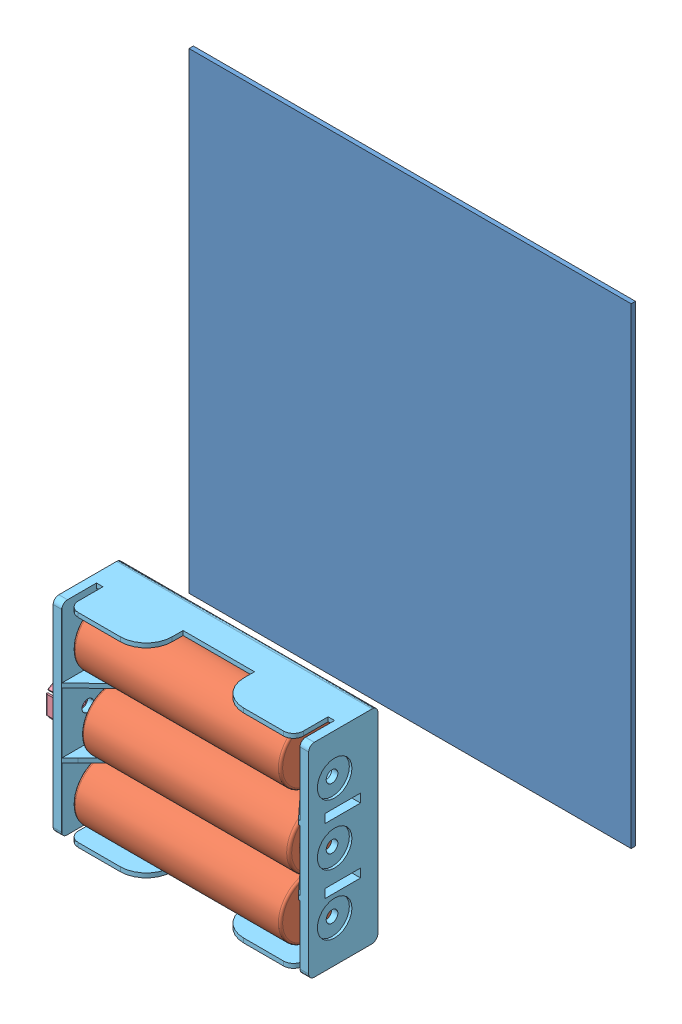
SolidWorks assembly FULL, configuration Default. Lengths in mm.
Overall size (123.67 108.97 143.43).
263 component instances, 61 part files, 2 mates.
Components (placement in the parent):
- PCB-1: PCB [Default] at origin size (102.11 108.97 21.15) (hidden)
  - Board-1: Board [Default] at origin size (102.11 108.97 0.41)
    - Open CASCADE STEP translator 6.8 2.1.1-1: Open CASCADE STEP translator 6.8 2.1.1 [Default] at (0 0 -0.4115) size (102.11 108.97 0.41)
  - arduino_nano-1: arduino_nano [Default] at (0 0 6.3234) size (45 18 18.6)
    - arduino_nano-1: arduino_nano [Default] at (189.4641 68.814 2.5274) x (-1 0 0) z (0 1 0) size (45 18.6 18)
      - nano-board-1: nano-board [Default] at origin size (43.2 4.61 18)
      - 2pin_header__02-1: 2pin_header__02 [Default] at (-1.143 1.6 -7.62) size (5 11.75 2.54)
      - 2pin_header__02-2: 2pin_header__02 [Default] at (-1.143 1.6 -5.08) size (5 11.75 2.54)
      - 2pin_header__02-3: 2pin_header__02 [Default] at (-1.143 1.6 -10.16) size (5 11.75 2.54)
      - 15pin_header__-1: 15pin_header__ [Default] x (0 0 1) z (1 0 0) size (2.54 11.75 38.1)
      - 15pin_header__-2: 15pin_header__ [Default] at (0 0 -15.24) x (0 0 1) z (1 0 0) size (2.54 11.75 38.1)
      - atmega328-1: atmega328 [Default] at (23.85 1.75 -7.62) x (-0.707107 0 0.707107) z (-0.707107 0 -0.707107) size (10 1.1 10)
      - ftdi_FT232rl-1: ftdi_FT232rl [Default] at (29.05 0 -7.67) x (0 0 -1) z (-1 0 0) size (9.25 1.9 10.2)
      - smt_resistor222-1: smt_resistor222 [Default] at (21.86 0 -5.8) x (0 0 -1) z (-1 0 0) size (1.7 0.6 3.8)
      - smt_resistor222-2: smt_resistor222 [Default] at (21.86 0 -9) x (0 0 -1) z (-1 0 0) size (1.7 0.6 3.8)
      - smt_resistor222-3: smt_resistor222 [Default] at (36.75 0 -7.6) x (0 0 -1) z (-1 0 0) size (1.7 0.6 3.8)
      - smt_resistor222-4: smt_resistor222 [Default] at (36.75 0 -12) x (0 0 -1) z (-1 0 0) size (1.7 0.6 3.8)
      - smt_resistor222-5: smt_resistor222 [Default] at (8.2 0 -2.6) x (0 0 -1) z (-1 0 0) size (1.7 0.6 3.8)
      - led-1: led [Default] at (10.4 1.6 -2.8) size (4 0.9 1.55)
      - led-2: led [Default] at (10.4 1.6 -5.55) size (4 0.9 1.55)
      - led-3: led [Default] at (10.4 1.6 -12.5) size (4 0.9 1.55)
      - led-4: led [Default] at (10.4 1.6 -9.05) size (4 0.9 1.55)
      - 16mhz_crystal_-_measured-1: 16mhz_crystal_-_measured [Default] at (18.5113 1.6 -3.5541) x (0.707107 0 0.707107) z (-0.707107 0 0.707107) size (3.4 0.8 2.01)
      - MINIUSB_-_MEASURED-1: MINIUSB_-_MEASURED [Default] at (38.98 1.65 -7.62) x (0 0 1) z (-1 0 0) size (10.9 4.96 10.42)
        - MINIUSBSHELL-1: MINIUSBSHELL [Default] at origin size (10.9 3.98 9.46)
        - MINIUSBCORE-1: MINIUSBCORE [Default] at (0 0 6.7) x (-1 0 0) z (0 0 -1) size (7.7 4.5 8.2)
        - MINI_USB_CONTACT-1: MINI_USB_CONTACT [Default] at (-1.6 0 5.7) x (-1 0 0) z (0 0 -1) size (0.53 2.55 9.41)
        - MINI_USB_CONTACT-2: MINI_USB_CONTACT [Default] at (-0.8 0 5.7) x (-1 0 0) z (0 0 -1) size (0.53 2.55 9.41)
        - MINI_USB_CONTACT-3: MINI_USB_CONTACT [Default] at (0 0 5.7) x (-1 0 0) z (0 0 -1) size (0.53 2.55 9.41)
        - MINI_USB_CONTACT-4: MINI_USB_CONTACT [Default] at (0.8 0 5.7) x (-1 0 0) z (0 0 -1) size (0.53 2.55 9.41)
        - MINI_USB_CONTACT-5: MINI_USB_CONTACT [Default] at (1.6 0 5.7) x (-1 0 0) z (0 0 -1) size (0.53 2.55 9.41)
      - cap106C-1: cap106C [Default] at (37.2 0 -3.3) x (0 0 1) z (1 0 0) size (1.7 1.81 4)
      - cap106C-2: cap106C [Default] at (7.9 0 -5.6) x (0 0 -1) z (-1 0 0) size (1.7 1.81 4)
      - reset_button-1: reset_button [Default] at (15.25 1.6 -8.05) x (0 0 -1) z (1 0 0) size (5.21 2.15 3)
        - reset_core-1: reset_core [Default] at origin size (5.21 2.15 2.8)
        - reset_shell-1: reset_shell [Default] at (0 1.65 0) x (0 0 1) z (-1 0 0) size (3 1.65 4)
      - nano_-_reg-1: nano_-_reg [Default] at (6.1 0 -10.16) x (0 0 -1) z (-1 0 0) size (6.5 1.69 8.3)
      - NANO_DIODE-1: NANO_DIODE [Default] at (11.43 0 -4.2) x (0 0 1) z (1 0 0) size (4.92 1.38 1.7)
      - 189_RESISTOR_PACK-1: 189_RESISTOR_PACK [Default] at (15.75 0 -10.85) x (0 0 1) z (1 0 0) size (3.2 0.51 3)
      - 102_RESISTOR_PACK-1: 102_RESISTOR_PACK [Default] at (15.75 0 -5.2) x (0 0 1) z (1 0 0) size (3.2 0.51 3)
  - M0-1: M0 [Default] at (0 0 4.4267) size (8.61 3.85 12.07)
    - SS12D00G4_1P2T_Straight-1: SS12D00G4_1P2T_Straight [Default] at (146.8249 131.405 2.54) x (1 0 0) z (0 0 1) size (8.61 3.85 12.07)
  - BMP-1: BMP [Default] at (0 0 2.9006) size (13.55 10.7 12.7)
    - GY-BME280-1: GY-BME280 [Default] at (155.5751 97.6629 0) x (0 1 0) z (0 0 1) size (10.7 13.55 3.64)
    - 1185083472-1: 1185083472 [Default] at (154.178 97.536 0) size (2.54 10.16 2.8)
      - Extruded-1: Extruded [Default] at origin size (2.54 10.16 2.8)
    - 1185083552-1: 1185083552 [Default] at (154.1779 93.7261 -3.2) x (0 1 0) z (0 0 1) size (1.06 1.06 12.7)
      - Cylinder-1: Cylinder [Default] at origin size (1.06 1.06 12.7)
    - 1185083552-2: 1185083552 [Default] at (154.1779 96.2661 -3.2) x (0 1 0) z (0 0 1) size (1.06 1.06 12.7)
      - Cylinder-1: Cylinder [Default] at origin size (1.06 1.06 12.7)
    - 1185083552-3: 1185083552 [Default] at (154.1779 98.8061 -3.2) x (0 1 0) z (0 0 1) size (1.06 1.06 12.7)
      - Cylinder-1: Cylinder [Default] at origin size (1.06 1.06 12.7)
    - 1185083552-4: 1185083552 [Default] at (154.1779 101.3461 -3.2) x (0 1 0) z (0 0 1) size (1.06 1.06 12.7)
      - Cylinder-1: Cylinder [Default] at origin size (1.06 1.06 12.7)
  - LVL_CONV-1: LVL_CONV [Default] at origin size (26 16 2.26)
    - TXS0108E-1: TXS0108E [Default] at (183.8961 73.6876 0) x (-1 0 0) z (0 1 0) size (26 2.26 16)
  - GPS-1: GPS [Default] at (0 0 9.8364) size (25.78 64.21 19.66)
    - GNSS_7_Click_v100_noAntenna-1: GNSS_7_Click_v100_noAntenna [Default] at (180.3023 96.7993 0.254) x (1 0 0) z (0 0 1) size (25.78 64.21 19.66)
      - GNSS_7_Click_v100.step-1: GNSS_7_Click_v100.step [Default] at origin size (25.78 64.21 19.66)
        - JP4.step-1: JP4.step [Default] at origin size (0.5 1 0.35)
          - User_Library-R_0402.step-1: User_Library-R_0402.step [Default] at (12.3191 18.1685 0) x (0 -1 0) z (0 0 1) size (1 0.5 0.35)
        - JP3.step-1: JP3.step [Default] at origin size (0.5 1 0.35)
          - User_Library-R_0402.step-1: User_Library-R_0402.step [Default] at (10.9221 18.161 0) x (0 -1 0) z (0 0 1) size (1 0.5 0.35)
        - JP2.step-1: JP2.step [Default] at origin size (0.5 1 0.35)
          - User_Library-R_0402.step-1: User_Library-R_0402.step [Default] at (9.5251 18.1685 0) x (0 -1 0) z (0 0 1) size (1 0.5 0.35)
        - JP1.step-1: JP1.step [Default] at origin size (0.5 1 0.35)
          - User_Library-R_0402.step-1: User_Library-R_0402.step [Default] at (8.1281 18.1685 0) x (0 -1 0) z (0 0 1) size (1 0.5 0.35)
        - MBD1.step-1: MBD1.step [Default] at origin size (25.78 20.32 12.19)
          - Header_1x8.step-1: Header_1x8.step [Default] at (-74.8548 -67.056 0) size (2.92 20.32 12.19)
            - PCB.step-1: PCB.step [Default] at origin size (2.92 20.32 12.19)
              - Free-Models.step-1: Free-Models.step [Default] at origin size (2.92 20.32 12.19)
                - 1240637040.step-1: 1240637040.step [Default] at (97.7778 84.836 -1.6002) x (0 -1 0) z (1 0 0) size (12.7 12.19 2.92)
                  - User_Library-PinHeaderX5-1_PinHeaderX5_Body_1.step-1: User_Library-PinHeaderX5-1_PinHeaderX5_Body_1.step [Default] at origin size (12.7 2.54 2.92)
                  - User_Library-PinHeaderX5-1_PinHeaderX5_Pins_1.step-1: User_Library-PinHeaderX5-1_PinHeaderX5_Pins_1.step [Default] at origin size (10.8 12.19 0.64)
                - 1240637040.step-2: 1240637040.step [Default] at (97.7778 77.216 -1.6002) x (0 -1 0) z (1 0 0) size (12.7 12.19 2.92)
                  - User_Library-PinHeaderX5-1_PinHeaderX5_Body_1.step-1: User_Library-PinHeaderX5-1_PinHeaderX5_Body_1.step [Default] at origin size (12.7 2.54 2.92)
                  - User_Library-PinHeaderX5-1_PinHeaderX5_Pins_1.step-1: User_Library-PinHeaderX5-1_PinHeaderX5_Pins_1.step [Default] at origin size (10.8 12.19 0.64)
          - Header_1x8.step-2: Header_1x8.step [Default] at (-97.7148 -67.056 0) size (2.92 20.32 12.19)
            - PCB.step-1: PCB.step [Default] at origin size (2.92 20.32 12.19)
              - Free-Models.step-1: Free-Models.step [Default] at origin size (2.92 20.32 12.19)
                - 1240637040.step-1: 1240637040.step [Default] at (97.7778 84.836 -1.6002) x (0 -1 0) z (1 0 0) size (12.7 12.19 2.92)
                  - User_Library-PinHeaderX5-1_PinHeaderX5_Body_1.step-1: User_Library-PinHeaderX5-1_PinHeaderX5_Body_1.step [Default] at origin size (12.7 2.54 2.92)
                  - User_Library-PinHeaderX5-1_PinHeaderX5_Pins_1.step-1: User_Library-PinHeaderX5-1_PinHeaderX5_Pins_1.step [Default] at origin size (10.8 12.19 0.64)
                - 1240637040.step-2: 1240637040.step [Default] at (97.7778 77.216 -1.6002) x (0 -1 0) z (1 0 0) size (12.7 12.19 2.92)
                  - User_Library-PinHeaderX5-1_PinHeaderX5_Body_1.step-1: User_Library-PinHeaderX5-1_PinHeaderX5_Body_1.step [Default] at origin size (12.7 2.54 2.92)
                  - User_Library-PinHeaderX5-1_PinHeaderX5_Pins_1.step-1: User_Library-PinHeaderX5-1_PinHeaderX5_Pins_1.step [Default] at origin size (10.8 12.19 0.64)
        - M1.step-1: M1.step [Default] at origin size (16 12.2 2.33)
          - NEO.step-1: NEO.step [Default] at (27.1803 74.1975 0.44) x (0 1 0) z (0 0 1) size (12.2 16 2.33)
            - NEO_PCB.step-1: NEO_PCB.step [Default] at (-47.5276 18.1124 -0.4125) size (12.2 16 0.9)
            - Shield_NEO.step-1: Shield_NEO.step [Default] at (-52.9276 25.2124 1.8175) x (0 -1 0) z (-1 0 0) size (15 1.4 11.6)
            - u-blox_NEO_label.step-1: u-blox_NEO_label.step [Default] at (-47.5276 18.1124 1.8175) x (0 1 0) z (1 0 0) size (13 0.07 10)
        - L1.step-1: L1.step [Default] at origin size (1 0.6 0.5)
          - User_Library-Chip_InductorINDC1005X60N.step-1: User_Library-Chip_InductorINDC1005X60N.step [Default] at (4.191 38.435 0.2433) x (1 0 0) z (0 0 1) size (1 0.6 0.5)
        - R9.step-1: R9.step [Default] at origin size (3.2 1.6 0.6)
          - User_Library-R_1206.step-1: User_Library-R_1206.step [Default] at (7.197 41.0209 0) x (-1 0 0) z (0 0 1) size (3.2 1.6 0.6)
        - C6.step-1: C6.step [Default] at origin size (2 1.25 0.6)
          - User_Library-SMD_CAPACITOR0805.step-1: User_Library-SMD_CAPACITOR0805.step [Default] at (7.7471 38.7351 0.3) x (1 0 0) z (0 -1 0) size (2 0.6 1.25)
        - R8.step-1: R8.step [Default] at origin size (1.6 0.9 0.5)
          - User_Library-R_0603.step-1: User_Library-R_0603.step [Default] at (19.8119 26.289 0) x (-1 0 0) z (0 0 1) size (1.6 0.9 0.5)
        - C3.step-1: C3.step [Default] at origin size (0.8 1.6 0.8)
          - User_Library-SMD_CAPACITOR0603.step-1: User_Library-SMD_CAPACITOR0603.step [Default] at (15.8749 17.7801 0.39) x (0 1 0) z (0 0 1) size (1.6 0.8 0.8)
        - C2.step-1: C2.step [Default] at origin size (0.8 1.6 0.8)
          - User_Library-SMD_CAPACITOR0603.step-1: User_Library-SMD_CAPACITOR0603.step [Default] at (13.9699 17.7801 0.39) x (0 1 0) z (0 0 1) size (1.6 0.8 0.8)
        - U2.step-1: U2.step [Default] at origin size (2.9 2.8 1.45)
          - User_Library-SOT23-5-2.step-1: User_Library-SOT23-5-2.step [Default] at (19.812 33.2739 0) x (-1 0 0) z (0 0 1) size (2.9 2.8 1.45)
        - U1.step-1: U1.step [Default] at origin size (2.9 2.82 1)
          - TSOT-23-6(S6).step-1: TSOT-23-6(S6).step [Default] at (19.1769 39.878 0) x (0 1 0) z (1 0 0) size (2.82 1 2.9)
        - R7.step-1: R7.step [Default] at origin size (0.9 1.6 0.5)
          - User_Library-R_0603.step-1: User_Library-R_0603.step [Default] at (12.446 35.8141 0) x (0 1 0) z (0 0 1) size (1.6 0.9 0.5)
        - R6.step-1: R6.step [Default] at origin size (0.9 1.6 0.5)
          - User_Library-R_0603.step-1: User_Library-R_0603.step [Default] at (10.922 35.8141 0) x (0 1 0) z (0 0 1) size (1.6 0.9 0.5)
        - R5.step-1: R5.step [Default] at origin size (0.9 1.6 0.5)
          - User_Library-R_0603.step-1: User_Library-R_0603.step [Default] at (9.398 35.8139 0) x (0 -1 0) z (0 0 1) size (1.6 0.9 0.5)
        - R4.step-1: R4.step [Default] at origin size (0.9 1.6 0.5)
          - User_Library-R_0603.step-1: User_Library-R_0603.step [Default] at (22.86 28.9559 0) x (0 -1 0) z (0 0 1) size (1.6 0.9 0.5)
        - R3.step-1: R3.step [Default] at origin size (1.6 0.9 0.5)
          - User_Library-R_0603.step-1: User_Library-R_0603.step [Default] at (19.8119 28.194 0) x (-1 0 0) z (0 0 1) size (1.6 0.9 0.5)
        - R2.step-1: R2.step [Default] at origin size (1.6 0.9 0.5)
          - User_Library-R_0603.step-1: User_Library-R_0603.step [Default] at (19.8119 30.099 0) x (-1 0 0) z (0 0 1) size (1.6 0.9 0.5)
        - R1.step-1: R1.step [Default] at origin size (2 1.25 0.5)
          - User_Library-R_0805.step-1: User_Library-R_0805.step [Default] at (12.1919 1.1429 0) x (-1 0 0) z (0 0 1) size (2 1.25 0.5)
        - Q1.step-1: Q1.step [Default] at origin size (2.25 2.2 1.1)
          - SOT323_(SC70-3)-1.step-1: SOT323_(SC70-3)-1.step [Default] at (15.3671 35.8141 0) x (0 -1 0) z (-1 0 0) size (2.2 1.1 2.25)
            - User_Library-SOT323_(SC70-3)-1_K_X_F6rper_1.step-1: User_Library-SOT323_(SC70-3)-1_K_X_F6rper_1.step [Default] x (0 0 -1) z (0 1 0) size (1.35 2.2 1)
            - User_Library-SOT323_(SC70-3)-1_Beschriftung_1.step-1: User_Library-SOT323_(SC70-3)-1_Beschriftung_1.step [Default] x (0 0 -1) z (0 1 0) size (0.8 1.45 0.06)
            - User_Library-SOT323_(SC70-3)-1_Pins_1.step-1: User_Library-SOT323_(SC70-3)-1_Pins_1.step [Default] at (0.65 0 0) x (0 0 1) z (0 1 0) size (0.6 0.4 0.9)
            - User_Library-SOT323_(SC70-3)-1_Pins_1.step-2: User_Library-SOT323_(SC70-3)-1_Pins_1.step [Default] at (-0.65 0 0) x (0 0 1) z (0 1 0) size (0.6 0.4 0.9)
            - User_Library-SOT323_(SC70-3)-1_Pins_1.step-3: User_Library-SOT323_(SC70-3)-1_Pins_1.step [Default] x (0 0 -1) z (0 1 0) size (0.6 0.4 0.9)
        - LD2.step-1: LD2.step [Default] at origin size (2.1 1.35 0.91)
          - CHIPLED-0805-RED.step-1: CHIPLED-0805-RED.step [Default] at (20.7009 21.3361 0) x (0 1 0) z (0 0 1) size (1.35 2.1 0.91)
        - LD1.step-1: LD1.step [Default] at origin size (2.02 1.25 1.1)
          - led_0805_green.step-1: led_0805_green.step [Default] at (16.5099 1.143 0) x (-1 0 0) z (0 0 1) size (2.02 1.25 1.1)
        - CN2.step-1: CN2.step [Default] at origin size (6.35 14.81 13.49)
          - User_Library-sma_ra_pcb_mount_molex.step-1: User_Library-sma_ra_pcb_mount_molex.step [Default] at (3.302 48.7682 0) x (0 1 0) z (0 0 1) size (14.81 6.35 13.49)
        - C5.step-1: C5.step [Default] at origin size (0.8 1.6 0.8)
          - User_Library-SMD_CAPACITOR0603.step-1: User_Library-SMD_CAPACITOR0603.step [Default] at (22.8791 32.8929 0.39) x (0 -1 0) z (0 0 1) size (1.6 0.8 0.8)
        - C4.step-1: C4.step [Default] at origin size (1.6 0.8 0.8)
          - User_Library-SMD_CAPACITOR0603.step-1: User_Library-SMD_CAPACITOR0603.step [Default] at (19.8121 36.4491 0.39) size (1.6 0.8 0.8)
        - C1.step-1: C1.step [Default] at origin size (3.7 2.93 2.03)
          - User_Library-AVX_BCASE.step-1: User_Library-AVX_BCASE.step [Default] at (7.0351 1.1431 0) x (1 0 0) z (0 0 1) size (3.7 2.93 2.03)
        - BAT1.step-1: BAT1.step [Default] at origin size (8 10.71 3.05)
          - keystone-PN2998TR.step-1: keystone-PN2998TR.step [Default] at (5.2705 9.272 2.9) x (0 -1 0) z (-1 0 0) size (10.71 3.05 8)
        - Board.step-1: Board.step [Default] at origin size (25.4 57.15 1.59)
  - GAL-1: GAL [Default] at (0 0 11.1875) size (25.78 64.21 19.66)
    - GNSS_7_Click_v100_noAntenna-1: GNSS_7_Click_v100_noAntenna [Default] at (211.1003 96.5199 0) x (1 0 0) z (0 0 1) size (25.78 64.21 19.66)
      - GNSS_7_Click_v100.step-1: GNSS_7_Click_v100.step [Default] at origin size (25.78 64.21 19.66)
        - JP4.step-1: JP4.step [Default] at origin size (0.5 1 0.35)
          - User_Library-R_0402.step-1: User_Library-R_0402.step [Default] at (12.3191 18.1685 0) x (0 -1 0) z (0 0 1) size (1 0.5 0.35)
        - JP3.step-1: JP3.step [Default] at origin size (0.5 1 0.35)
          - User_Library-R_0402.step-1: User_Library-R_0402.step [Default] at (10.9221 18.161 0) x (0 -1 0) z (0 0 1) size (1 0.5 0.35)
        - JP2.step-1: JP2.step [Default] at origin size (0.5 1 0.35)
          - User_Library-R_0402.step-1: User_Library-R_0402.step [Default] at (9.5251 18.1685 0) x (0 -1 0) z (0 0 1) size (1 0.5 0.35)
        - JP1.step-1: JP1.step [Default] at origin size (0.5 1 0.35)
          - User_Library-R_0402.step-1: User_Library-R_0402.step [Default] at (8.1281 18.1685 0) x (0 -1 0) z (0 0 1) size (1 0.5 0.35)
        - MBD1.step-1: MBD1.step [Default] at origin size (25.78 20.32 12.19)
          - Header_1x8.step-1: Header_1x8.step [Default] at (-74.8548 -67.056 0) size (2.92 20.32 12.19)
            - PCB.step-1: PCB.step [Default] at origin size (2.92 20.32 12.19)
              - Free-Models.step-1: Free-Models.step [Default] at origin size (2.92 20.32 12.19)
                - 1240637040.step-1: 1240637040.step [Default] at (97.7778 84.836 -1.6002) x (0 -1 0) z (1 0 0) size (12.7 12.19 2.92)
                  - User_Library-PinHeaderX5-1_PinHeaderX5_Body_1.step-1: User_Library-PinHeaderX5-1_PinHeaderX5_Body_1.step [Default] at origin size (12.7 2.54 2.92)
                  - User_Library-PinHeaderX5-1_PinHeaderX5_Pins_1.step-1: User_Library-PinHeaderX5-1_PinHeaderX5_Pins_1.step [Default] at origin size (10.8 12.19 0.64)
                - 1240637040.step-2: 1240637040.step [Default] at (97.7778 77.216 -1.6002) x (0 -1 0) z (1 0 0) size (12.7 12.19 2.92)
                  - User_Library-PinHeaderX5-1_PinHeaderX5_Body_1.step-1: User_Library-PinHeaderX5-1_PinHeaderX5_Body_1.step [Default] at origin size (12.7 2.54 2.92)
                  - User_Library-PinHeaderX5-1_PinHeaderX5_Pins_1.step-1: User_Library-PinHeaderX5-1_PinHeaderX5_Pins_1.step [Default] at origin size (10.8 12.19 0.64)
          - Header_1x8.step-2: Header_1x8.step [Default] at (-97.7148 -67.056 0) size (2.92 20.32 12.19)
            - PCB.step-1: PCB.step [Default] at origin size (2.92 20.32 12.19)
              - Free-Models.step-1: Free-Models.step [Default] at origin size (2.92 20.32 12.19)
                - 1240637040.step-1: 1240637040.step [Default] at (97.7778 84.836 -1.6002) x (0 -1 0) z (1 0 0) size (12.7 12.19 2.92)
                  - User_Library-PinHeaderX5-1_PinHeaderX5_Body_1.step-1: User_Library-PinHeaderX5-1_PinHeaderX5_Body_1.step [Default] at origin size (12.7 2.54 2.92)
                  - User_Library-PinHeaderX5-1_PinHeaderX5_Pins_1.step-1: User_Library-PinHeaderX5-1_PinHeaderX5_Pins_1.step [Default] at origin size (10.8 12.19 0.64)
                - 1240637040.step-2: 1240637040.step [Default] at (97.7778 77.216 -1.6002) x (0 -1 0) z (1 0 0) size (12.7 12.19 2.92)
                  - User_Library-PinHeaderX5-1_PinHeaderX5_Body_1.step-1: User_Library-PinHeaderX5-1_PinHeaderX5_Body_1.step [Default] at origin size (12.7 2.54 2.92)
                  - User_Library-PinHeaderX5-1_PinHeaderX5_Pins_1.step-1: User_Library-PinHeaderX5-1_PinHeaderX5_Pins_1.step [Default] at origin size (10.8 12.19 0.64)
        - M1.step-1: M1.step [Default] at origin size (16 12.2 2.33)
          - NEO.step-1: NEO.step [Default] at (27.1803 74.1975 0.44) x (0 1 0) z (0 0 1) size (12.2 16 2.33)
            - NEO_PCB.step-1: NEO_PCB.step [Default] at (-47.5276 18.1124 -0.4125) size (12.2 16 0.9)
            - Shield_NEO.step-1: Shield_NEO.step [Default] at (-52.9276 25.2124 1.8175) x (0 -1 0) z (-1 0 0) size (15 1.4 11.6)
            - u-blox_NEO_label.step-1: u-blox_NEO_label.step [Default] at (-47.5276 18.1124 1.8175) x (0 1 0) z (1 0 0) size (13 0.07 10)
        - L1.step-1: L1.step [Default] at origin size (1 0.6 0.5)
          - User_Library-Chip_InductorINDC1005X60N.step-1: User_Library-Chip_InductorINDC1005X60N.step [Default] at (4.191 38.435 0.2433) x (1 0 0) z (0 0 1) size (1 0.6 0.5)
        - R9.step-1: R9.step [Default] at origin size (3.2 1.6 0.6)
          - User_Library-R_1206.step-1: User_Library-R_1206.step [Default] at (7.197 41.0209 0) x (-1 0 0) z (0 0 1) size (3.2 1.6 0.6)
        - C6.step-1: C6.step [Default] at origin size (2 1.25 0.6)
          - User_Library-SMD_CAPACITOR0805.step-1: User_Library-SMD_CAPACITOR0805.step [Default] at (7.7471 38.7351 0.3) x (1 0 0) z (0 -1 0) size (2 0.6 1.25)
        - R8.step-1: R8.step [Default] at origin size (1.6 0.9 0.5)
          - User_Library-R_0603.step-1: User_Library-R_0603.step [Default] at (19.8119 26.289 0) x (-1 0 0) z (0 0 1) size (1.6 0.9 0.5)
        - C3.step-1: C3.step [Default] at origin size (0.8 1.6 0.8)
          - User_Library-SMD_CAPACITOR0603.step-1: User_Library-SMD_CAPACITOR0603.step [Default] at (15.8749 17.7801 0.39) x (0 1 0) z (0 0 1) size (1.6 0.8 0.8)
        - C2.step-1: C2.step [Default] at origin size (0.8 1.6 0.8)
          - User_Library-SMD_CAPACITOR0603.step-1: User_Library-SMD_CAPACITOR0603.step [Default] at (13.9699 17.7801 0.39) x (0 1 0) z (0 0 1) size (1.6 0.8 0.8)
        - U2.step-1: U2.step [Default] at origin size (2.9 2.8 1.45)
          - User_Library-SOT23-5-2.step-1: User_Library-SOT23-5-2.step [Default] at (19.812 33.2739 0) x (-1 0 0) z (0 0 1) size (2.9 2.8 1.45)
        - U1.step-1: U1.step [Default] at origin size (2.9 2.82 1)
          - TSOT-23-6(S6).step-1: TSOT-23-6(S6).step [Default] at (19.1769 39.878 0) x (0 1 0) z (1 0 0) size (2.82 1 2.9)
        - R7.step-1: R7.step [Default] at origin size (0.9 1.6 0.5)
          - User_Library-R_0603.step-1: User_Library-R_0603.step [Default] at (12.446 35.8141 0) x (0 1 0) z (0 0 1) size (1.6 0.9 0.5)
        - R6.step-1: R6.step [Default] at origin size (0.9 1.6 0.5)
          - User_Library-R_0603.step-1: User_Library-R_0603.step [Default] at (10.922 35.8141 0) x (0 1 0) z (0 0 1) size (1.6 0.9 0.5)
        - R5.step-1: R5.step [Default] at origin size (0.9 1.6 0.5)
          - User_Library-R_0603.step-1: User_Library-R_0603.step [Default] at (9.398 35.8139 0) x (0 -1 0) z (0 0 1) size (1.6 0.9 0.5)
        - R4.step-1: R4.step [Default] at origin size (0.9 1.6 0.5)
          - User_Library-R_0603.step-1: User_Library-R_0603.step [Default] at (22.86 28.9559 0) x (0 -1 0) z (0 0 1) size (1.6 0.9 0.5)
        - R3.step-1: R3.step [Default] at origin size (1.6 0.9 0.5)
          - User_Library-R_0603.step-1: User_Library-R_0603.step [Default] at (19.8119 28.194 0) x (-1 0 0) z (0 0 1) size (1.6 0.9 0.5)
        - R2.step-1: R2.step [Default] at origin size (1.6 0.9 0.5)
          - User_Library-R_0603.step-1: User_Library-R_0603.step [Default] at (19.8119 30.099 0) x (-1 0 0) z (0 0 1) size (1.6 0.9 0.5)
        - R1.step-1: R1.step [Default] at origin size (2 1.25 0.5)
          - User_Library-R_0805.step-1: User_Library-R_0805.step [Default] at (12.1919 1.1429 0) x (-1 0 0) z (0 0 1) size (2 1.25 0.5)
        - Q1.step-1: Q1.step [Default] at origin size (2.25 2.2 1.1)
          - SOT323_(SC70-3)-1.step-1: SOT323_(SC70-3)-1.step [Default] at (15.3671 35.8141 0) x (0 -1 0) z (-1 0 0) size (2.2 1.1 2.25)
            - User_Library-SOT323_(SC70-3)-1_K_X_F6rper_1.step-1: User_Library-SOT323_(SC70-3)-1_K_X_F6rper_1.step [Default] x (0 0 -1) z (0 1 0) size (1.35 2.2 1)
            - User_Library-SOT323_(SC70-3)-1_Beschriftung_1.step-1: User_Library-SOT323_(SC70-3)-1_Beschriftung_1.step [Default] x (0 0 -1) z (0 1 0) size (0.8 1.45 0.06)
            - User_Library-SOT323_(SC70-3)-1_Pins_1.step-1: User_Library-SOT323_(SC70-3)-1_Pins_1.step [Default] at (0.65 0 0) x (0 0 1) z (0 1 0) size (0.6 0.4 0.9)
            - User_Library-SOT323_(SC70-3)-1_Pins_1.step-2: User_Library-SOT323_(SC70-3)-1_Pins_1.step [Default] at (-0.65 0 0) x (0 0 1) z (0 1 0) size (0.6 0.4 0.9)
            - User_Library-SOT323_(SC70-3)-1_Pins_1.step-3: User_Library-SOT323_(SC70-3)-1_Pins_1.step [Default] x (0 0 -1) z (0 1 0) size (0.6 0.4 0.9)
        - LD2.step-1: LD2.step [Default] at origin size (2.1 1.35 0.91)
          - CHIPLED-0805-RED.step-1: CHIPLED-0805-RED.step [Default] at (20.7009 21.3361 0) x (0 1 0) z (0 0 1) size (1.35 2.1 0.91)
        - LD1.step-1: LD1.step [Default] at origin size (2.02 1.25 1.1)
          - led_0805_green.step-1: led_0805_green.step [Default] at (16.5099 1.143 0) x (-1 0 0) z (0 0 1) size (2.02 1.25 1.1)
        - CN2.step-1: CN2.step [Default] at origin size (6.35 14.81 13.49)
          - User_Library-sma_ra_pcb_mount_molex.step-1: User_Library-sma_ra_pcb_mount_molex.step [Default] at (3.302 48.7682 0) x (0 1 0) z (0 0 1) size (14.81 6.35 13.49)
        - C5.step-1: C5.step [Default] at origin size (0.8 1.6 0.8)
          - User_Library-SMD_CAPACITOR0603.step-1: User_Library-SMD_CAPACITOR0603.step [Default] at (22.8791 32.8929 0.39) x (0 -1 0) z (0 0 1) size (1.6 0.8 0.8)
        - C4.step-1: C4.step [Default] at origin size (1.6 0.8 0.8)
          - User_Library-SMD_CAPACITOR0603.step-1: User_Library-SMD_CAPACITOR0603.step [Default] at (19.8121 36.4491 0.39) size (1.6 0.8 0.8)
        - C1.step-1: C1.step [Default] at origin size (3.7 2.93 2.03)
          - User_Library-AVX_BCASE.step-1: User_Library-AVX_BCASE.step [Default] at (7.0351 1.1431 0) x (1 0 0) z (0 0 1) size (3.7 2.93 2.03)
        - BAT1.step-1: BAT1.step [Default] at origin size (8 10.71 3.05)
          - keystone-PN2998TR.step-1: keystone-PN2998TR.step [Default] at (5.2705 9.272 2.9) x (0 -1 0) z (-1 0 0) size (10.71 3.05 8)
        - Board.step-1: Board.step [Default] at origin size (25.4 57.15 1.59)
  - M1-1: M1 [Default] at (0 0 4.463) size (8.61 3.85 12.07)
    - SS12D00G4_1P2T_Straight-1: SS12D00G4_1P2T_Straight [Default] at (146.8249 124.547 2.54) x (1 0 0) z (0 0 1) size (8.61 3.85 12.07)
  - SD-1: SD [Default] at (0 0 6.1612) size (46.9 24 6.7)
    - MicroSD_Reader_Assembly-1: MicroSD_Reader_Assembly [Default] at (210.8201 82.6769 0.127) x (-1 0 0) z (0 0 1) size (46.9 24 6.7)
      - sdreader-1: sdreader [Default] at (-11.2744 2.632 -3.2) size (46.9 24 6.7)
        - Open CASCADE STEP translator 6.8 2.9.1.1.1-1: Open CASCADE STEP translator 6.8 2.9.1.1.1 [Default] at origin size (46.9 24 6.7)
      - AMS1117-1: AMS1117 [Default] at (-0.4339 -2.128 -1.13) x (1 0 0) z (0 -1 0) size (6.51 1.86 7)
      - card_sd-1: card_sd [Default] at (-21.187 5.4466 -0.36) x (0 -1 0) z (0 0 1) size (11 15 0.82)
  - LoRA_-_ES32-1: LoRA_-_ES32 [Default] at (0 0 3.4049) size (24 52.5 13.62)
    - STEP-7pin-61300711121-rev1-1: STEP-7pin-61300711121-rev1 [Default] at (165.6081 105.664 1.2975) x (1 0 0) z (0 -1 0) size (17.78 11.54 2.54)
      - 6130xx11121_PIN-1: 6130xx11121_PIN [Default] at (-7.62 1.5 0) x (1 0 0) z (0 -1 0) size (0.64 0.64 11.54)
      - 6130xx11121_PIN-2: 6130xx11121_PIN [Default] at (-5.08 1.5 0) x (1 0 0) z (0 -1 0) size (0.64 0.64 11.54)
      - 6130xx11121_PIN-3: 6130xx11121_PIN [Default] at (-2.54 1.5 0) x (1 0 0) z (0 -1 0) size (0.64 0.64 11.54)
      - 6130xx11121_PIN-4: 6130xx11121_PIN [Default] at (0 1.5 0) x (1 0 0) z (0 -1 0) size (0.64 0.64 11.54)
      - 6130xx11121_PIN-5: 6130xx11121_PIN [Default] at (2.54 1.5 0) x (1 0 0) z (0 -1 0) size (0.64 0.64 11.54)
      - 6130xx11121_PIN-6: 6130xx11121_PIN [Default] at (5.08 1.5 0) x (1 0 0) z (0 -1 0) size (0.64 0.64 11.54)
      - 6130xx11121_PIN-7: 6130xx11121_PIN [Default] at (7.62 1.5 0) x (1 0 0) z (0 -1 0) size (0.64 0.64 11.54)
      - 61300711121-1: 61300711121 [Default] at origin size (17.78 2.54 2.54)
    - E32-TTL-1: E32-TTL [Default] at (165.6386 192.5439 25.4) x (0 1 0) z (1 0 0) size (52.5 13.62 24)
      - E32-TTL-1W_Predeterminado-1: E32-TTL-1W_Predeterminado [Default] at (-66.873 -19.9517 0) size (43 3.79 24)
      - SMA_CONNECTOR_-_EMPCB.SMAFSTJ.B.HT-1: SMA_CONNECTOR_-_EMPCB.SMAFSTJ.B.HT [Default] at (-43.773 -15.0017 10.2201) x (0 0 1) z (1 0 0) size (6.58 6.47 13.3)
      - 05__HEADER-3WAY-1ROW-2.54MM-VERTICAL-PCB_Predeterminado-1: 05__HEADER-3WAY-1ROW-2.54MM-VERTICAL-PCB_Predeterminado [Default] at (-87.6961 -24.2405 2.52) x (0 -1 0) z (0 0 1) size (11.55 2.54 7.62)
      - 05__HEADER-3WAY-1ROW-2.54MM-VERTICAL-PCB_Predeterminado-2: 05__HEADER-3WAY-1ROW-2.54MM-VERTICAL-PCB_Predeterminado [Default] at (-87.6961 -24.2405 -5.1) x (0 -1 0) z (0 0 1) size (11.55 2.54 7.62)
      - HEADER-1WAY-1ROW-2.54MM-VERTICAL-PCB_Predeterminado-1: HEADER-1WAY-1ROW-2.54MM-VERTICAL-PCB_Predeterminado [Default] at (-86.893 -19.9517 -7.64) x (0 -1 0) z (-1 0 0) size (11.54 2.54 2.54)
- Assem174^FULL-1: Assem174^FULL [Default] at (0.1001 -86.6446 224.0631) size (123.67 108.97 94.51) (virtual)
  - SuperiorPCB^Assem174_FULL-1: SuperiorPCB^Assem174_FULL [Default] at (-217.1852 -127.0685 1798.4663) x (0.837169 0 0.546944) z (-0.546944 0 0.837169) size (86.03 108.97 56.68) (virtual)
  - Battery-1: Battery [Default] at (223.6014 97.691 30.4054) x (1 0 0) z (0 0.001809 0.999998) size (62.2 47.03 16.09)
    - AA BATTERY-1: AA BATTERY [Default] at (32.71 79.0018 -164.738) x (0 -0.000009 -1) z (-1 0 0) size (14 14 49.5)
    - AA BATTERY-2: AA BATTERY [Default] at (-13.29 94.0018 -164.7109) x (0 -0.000009 -1) z (1 0 0) size (14 14 49.5)
    - AA BATTERY-3: AA BATTERY [Default] at (32.71 110.0018 -164.682) x (0 0.000009 1) z (-1 0 0) size (14 14 49.5)
    - POS TERMINAL-1: POS TERMINAL [Default] at (-19.19 108.5 -163.6847) x (0 -0.001552 0.999999) z (-1 0 0) size (7 7 3.1)
    - NEG TERMINAL-1: NEG TERMINAL [Default] at (-19.79 94.5 -163.71) x (0 0 1) z (-1 0 0) size (9 10.39 3.8)
    - 3 aa battery-1: 3 aa battery [Default] at (64.21 76.0181 -173.7435) x (1 0 0) z (0 -0.001809 0.999998) size (59 47 16)
Mates (geometry in assembly coordinates):
- Parallel1: parallel aligned: plane of PCB-1/Board-1/Open CASCADE STEP translator 6.8 2.1.1-1 through (139.7 158.75 -0.4115) normal (0 1 0); plane of Assem174^FULL-1/SuperiorPCB^Assem174_FULL-1 through (241.808 158.75 1) normal (0 1 0)
- Parallel2: parallel aligned: plane of PCB-1/Board-1/Open CASCADE STEP translator 6.8 2.1.1-1 through (241.808 158.75 -0.4115) normal (1 0 0); plane of Assem174^FULL-1/SuperiorPCB^Assem174_FULL-1 through (241.808 49.784 1) normal (1 0 0)
